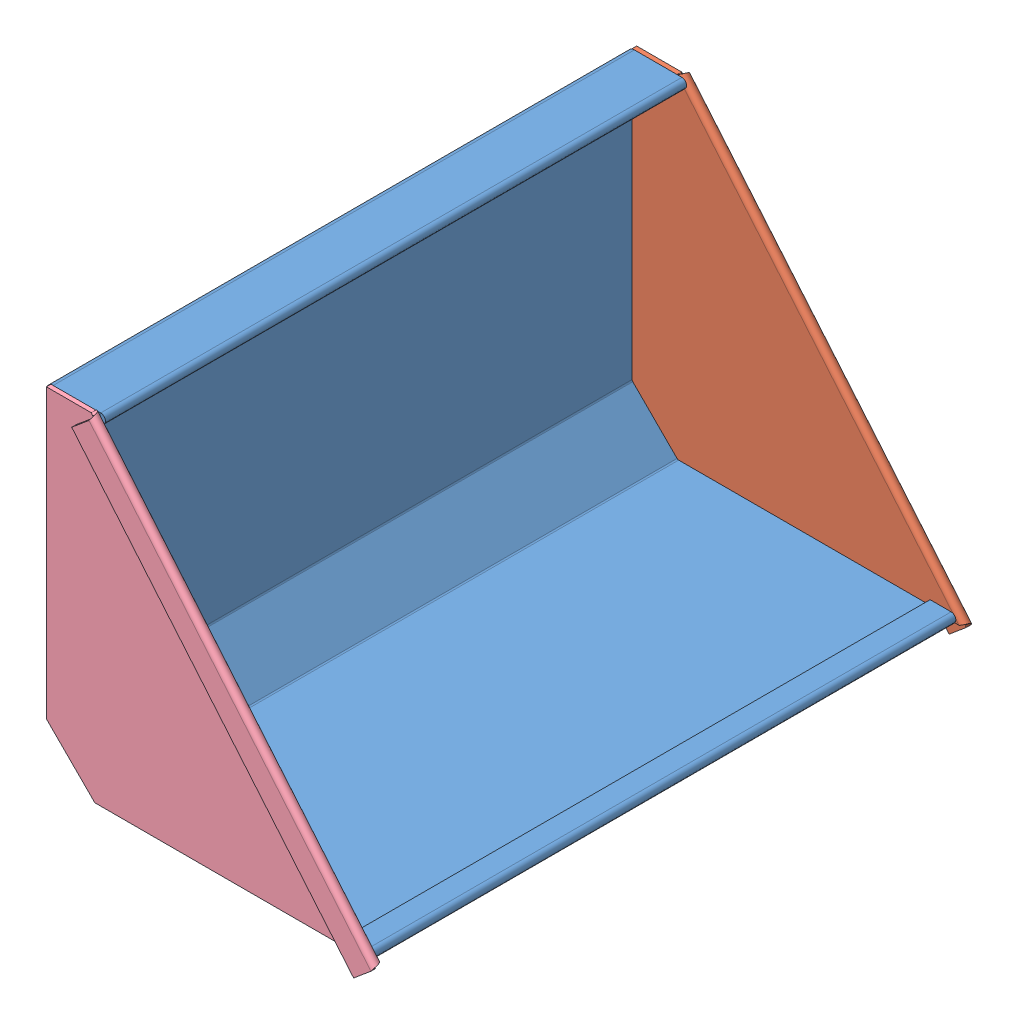
SolidWorks assembly E&1, configuration Predeterminado. Lengths in mm.
Overall size (133.71 117.42 198.4).
4 component instances, 4 part files, 7 mates.
Components (placement in the parent):
- P61.2-1: P61.2 [Predeterminado] at origin size (108.44 111.54 192)
- P61.3-4: P61.3 [Predeterminado] at (50.0607 -0.9607 -97.5) x (-1 0 0) z (0 0 -1) size (109.71 117.42 3.3)
- P61.1-1: P61.1 [Predeterminado] at (-62.9393 50.3658 0) x (0 0 1) z (-1 0 0) size (60 70 22.5)
- SimetríaP61.3-6: SimetríaP61.3 [Predeterminado] at (50.0607 -0.9607 97.5) x (-1 0 0) z (0 0 -1) size (109.71 117.42 3.3)
Mates (geometry in assembly coordinates):
- Coincidente16: coincident anti-aligned: plane of P61.2-1 through (-61.4393 -1.5 0) normal (-1 0 0); plane of P61.1-1 through (-61.4393 50.3658 0) normal (1 0 0)
- Coincidente20: coincident anti-aligned: line of P61.2-1 through (-43.4893 110.0393 -96) axis (-1 0 0); line of P61.3-4 through (-59.9393 110.0393 -96) axis (1 0 0)
- Coincidente22: coincident anti-aligned: plane of P61.2-1 through (-47 -1.5 -96) normal (0 0 -1); plane of P61.3-4 through (50.0607 -0.9607 -96) normal (0 0 1)
- Coincidente23: coincident anti-aligned: line of P61.2-1 through (-59.9393 107.8027 -96) axis (0 -1 0); line of P61.3-4 through (-59.9393 15.0393 -96) axis (0 1 0)
- Coincidente27: coordinate: point of P61.2-1
- Coincidente29: coincident aligned: plane of P61.1-1 through (-62.9393 50.3658 0) normal (0 0 1)
- Coincidente31: coincident anti-aligned: line of P61.2-1 through (-61.4393 15.3658 96) axis (0 0 -1); line of P61.1-1 through (-61.4393 15.3658 -27.7634) axis (0 0 1)
